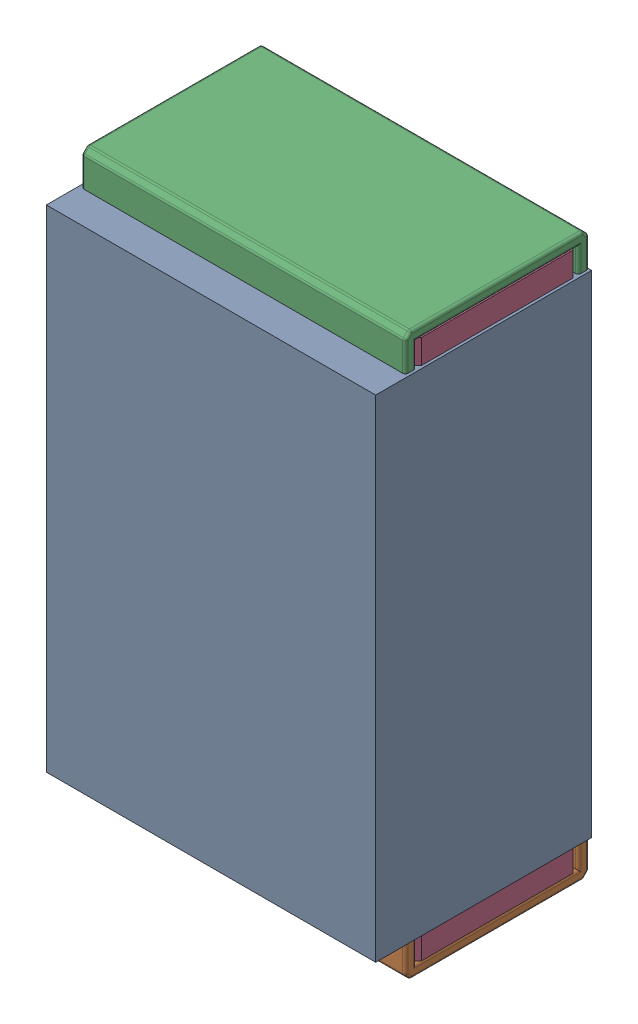
SolidWorks assembly R11, configuration Default. Lengths in mm.
Overall size (0.61 1.04 0.4).
3 component instances, 2 part files, 0 mates.
Components (placement in the parent):
- 1088881848-1: 1088881848 [Default] at (13.25 34.65 0) size (0.61 0.91 0.4)
  - Extruded-1-1: Extruded-1 [Default] at origin size (0.61 0.91 0.4)
- R0402-1: R0402 [Default] at (13.25 34.6499 0) x (0 -1 0) z (-1 0 0) size (1.04 0.34 0.6)
